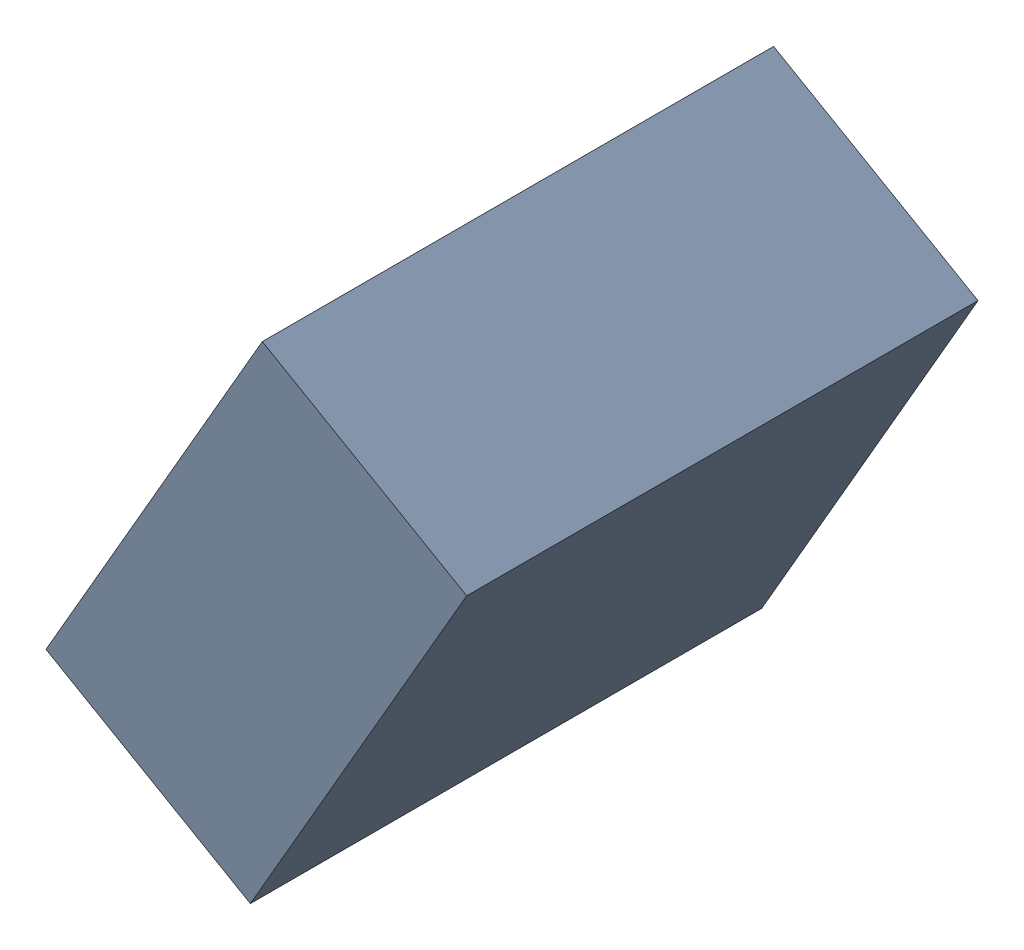
SolidWorks assembly C24_TDA6, configuration Standard. Lengths in mm.
Overall size (1.07 1.25 1.3).
2 component instances, 1 part files, 0 mates.
Components (placement in the parent):
- 885543328-1: 885543328 [Standard] at (-37.9824 23.6049 0) size (1.07 1.25 1.3)
  - Extruded_26-1: Extruded_26 [Standard] at origin size (1.07 1.25 1.3)
